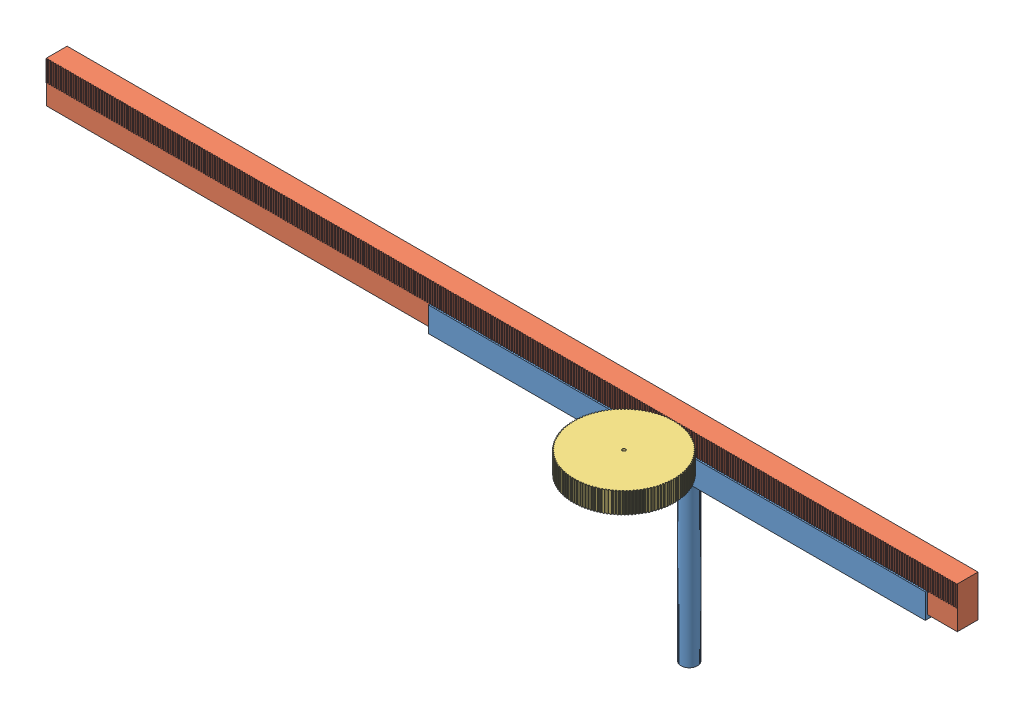
SolidWorks assembly arm, configuration Default. Lengths in mm.
Overall size (550 127.5 81.35).
3 component instances, 3 part files, 7 mates.
Components (placement in the parent):
- Part3-1: Part3 [Default] at (74.1401 147.116 261.7533) x (1 0 0) z (0 0 -1) size (300 115 15)
- rack of arm-1: rack of arm [Default] at (-32.765 159.616 268.0033) x (1 0 0) z (0 0 -1) size (550 25 13)
- pinion-2: pinion [Default] at (71.4881 159.616 298.5192) x (0.969077 0 0.246757) z (0.246757 0 -0.969077) size (60.99 12.5 61)
Mates (geometry in assembly coordinates):
- Coincident1: coincident anti-aligned: plane of Part3-1 through (224.1401 134.616 268.0033) normal (0 0 -1); plane of rack of arm-1 through (-307.765 134.616 268.0033) normal (0 0 1)
- Coincident2: coincident anti-aligned: plane of Part3-1 through (74.1401 134.616 261.7533) normal (0 1 0); plane of rack of arm-1 through (-32.765 134.616 268.0033) normal (0 -1 0)
- Coincident6: coincident: plane of rack of arm-1 through (12.2493 159.616 268.0033) normal (0 1 0); plane of pinion-2 through (47.1931 159.616 312.043) normal (0 1 0)
- Coincident7: coincident: plane of rack of arm-1 through (-190.1937 147.116 269.8603) normal (0 0 1); plane of pinion-2 through (39.2523 159.616 269.8603) normal (0 0 -1)
- Parallel1: parallel aligned: plane of rack of arm-1 through (-307.765 134.616 268.0033) normal (0 0 1); plane of pinion-2 through (71.4881 147.116 329.0192) normal (0 0 1)
- Parallel2: parallel aligned: plane of rack of arm-1 through (-32.765 159.616 268.0033) normal (0 1 0); plane of pinion-2 through (71.4881 159.616 298.5192) normal (0 1 0)
- Coincident9: coincident aligned: plane of rack of arm-1 through (-32.765 159.616 268.0033) normal (0 1 0); plane of pinion-2 through (71.4881 159.616 298.5192) normal (0 1 0)
